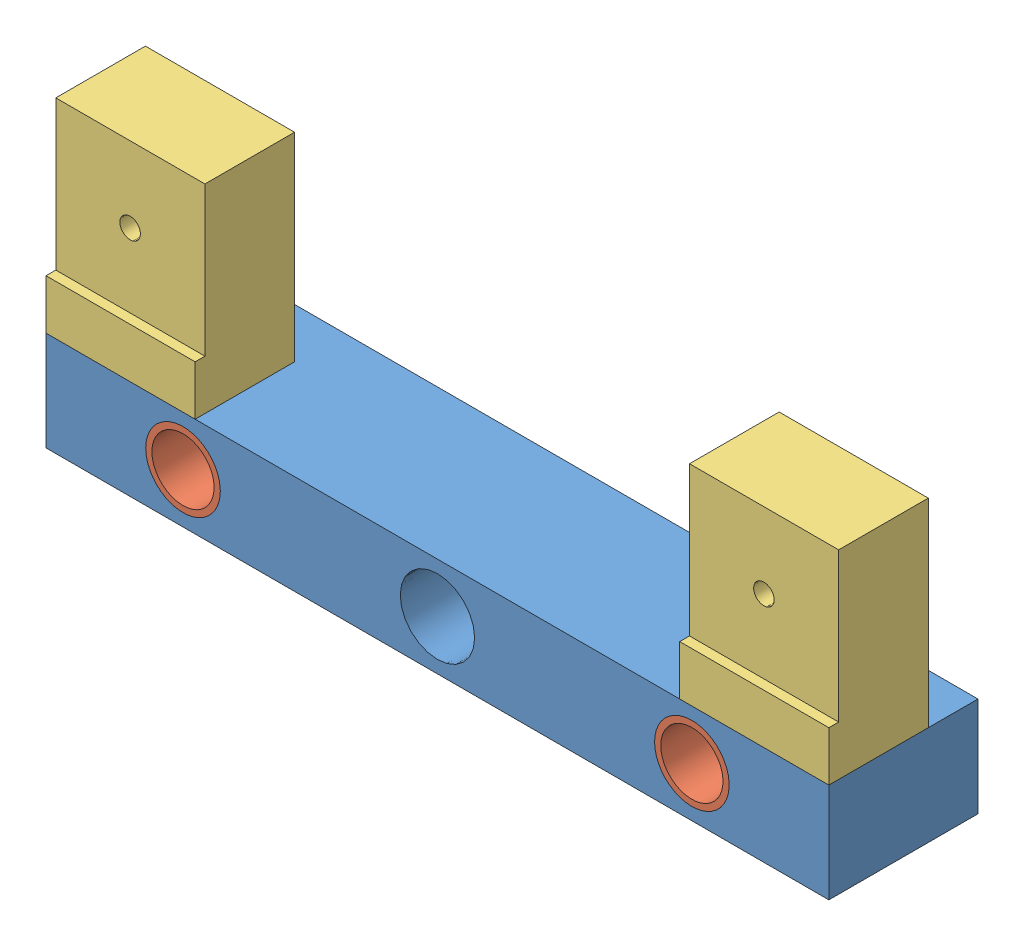
SolidWorks assembly Assem1, configuration Default. Lengths in mm.
Overall size (400 152.4 76.2).
5 component instances, 3 part files, 10 mates.
Components (placement in the parent):
- MovingBlock-1: MovingBlock [Default] at (-226.6054 1.7441 118.3917) size (400 50.8 76.2)
- 67model-1: 67model [Default] at (-156.6054 27.1441 42.1917) size (38.1 38.1 76.2)
- 67model-2: 67model [Default] at (103.3946 27.1441 42.1917) size (38.1 38.1 76.2)
- ClampBlock-1: ClampBlock [Default] at (-226.6054 52.5441 118.3917) size (76.2 101.6 50.8)
- ClampBlock-2: ClampBlock [Default] at (97.1946 52.5441 118.3917) size (76.2 101.6 50.8)
Mates (geometry in assembly coordinates):
- Concentric1: concentric: cylinder of MovingBlock-1 through (-156.6054 27.1441 42.1917) axis (0 0 1) radius 19; cylinder of 67model-1 through (-156.6054 27.1441 118.3917) axis (0 0 -1) radius 19.05
- Concentric2: concentric: cylinder of MovingBlock-1 through (103.3946 27.1441 42.1917) axis (0 0 1) radius 19; cylinder of 67model-2 through (103.3946 27.1441 118.3917) axis (0 0 -1) radius 19.05
- Coincident1: coincident aligned: circle of MovingBlock-1; plane of 67model-1 through (-156.6054 27.1441 118.3917) normal (0 0 1)
- Coincident2: coincident aligned: plane of MovingBlock-1 through (-226.6054 52.5441 118.3917) normal (0 0 1); circle of 67model-2
- Coincident3: coincident: plane of MovingBlock-1 through (-226.6054 52.5441 118.3917) normal (0 0 1); plane of ClampBlock-1 through (-226.6054 154.1441 118.3917) normal (0 0 1)
- Coincident4: coincident: plane of MovingBlock-1 through (-226.6054 52.5441 118.3917) normal (0 0 1); plane of ClampBlock-2 through (97.1946 154.1441 118.3917) normal (0 0 1)
- Coincident5: coincident: plane of MovingBlock-1 through (-226.6054 52.5441 42.1917) normal (0 1 0); plane of ClampBlock-1 through (-226.6054 52.5441 67.5917) normal (0 -1 0)
- Coincident6: coincident: plane of MovingBlock-1 through (-226.6054 52.5441 42.1917) normal (0 1 0); plane of ClampBlock-2 through (97.1946 52.5441 67.5917) normal (0 -1 0)
- Coincident7: coincident aligned: plane of MovingBlock-1 through (173.3946 52.5441 118.3917) normal (1 0 0); plane of ClampBlock-2 through (173.3946 154.1441 118.3917) normal (1 0 0)
- Coincident8: coincident aligned: plane of MovingBlock-1 through (-226.6054 52.5441 118.3917) normal (-1 0 0); plane of ClampBlock-1 through (-226.6054 154.1441 118.3917) normal (-1 0 0)
